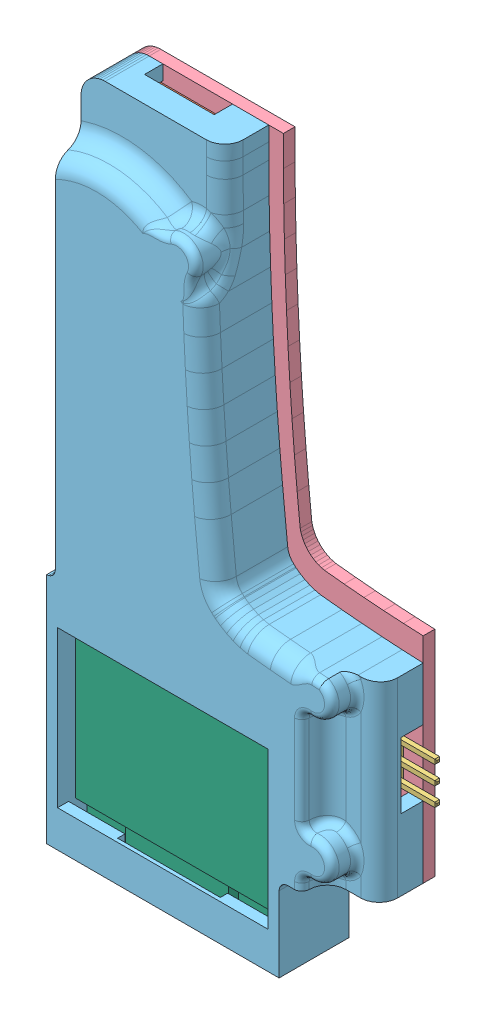
SolidWorks assembly 机身, configuration 默认. Lengths in mm.
Overall size (45.22 90.49 12.7).
35 component instances, 6 part files, 6 mates.
Components (placement in the parent):
- Controller_body-1: Controller_body [默认] at (-135.1163 108.4496 -1.41) size (44.02 78.99 5.56)
  - Controller_body.step-1: Controller_body.step [默认] at origin size (44.02 78.99 5.56)
    - R_0805_2012Metric.step-1: R_0805_2012Metric.step [默认] at (97.536 -98.298 1.63) x (-1 0 0) z (0 0 1) size (2 1.2 0.45)
      - SOLID.step-1: SOLID.step [默认] at origin size (2 1.2 0.45)
    - R_0805_2012Metric.step-2: R_0805_2012Metric.step [默认] at (85.106 -86.36 1.63) x (-1 0 0) z (0 0 1) size (2 1.2 0.45)
      - SOLID.step-1: SOLID.step [默认] at origin size (2 1.2 0.45)
    - TE_84953-6_1x06-1MP_P1.0mm_Horizontal.step-1: TE_84953-6_1x06-1MP_P1.0mm_Horizontal.step [默认] at (89.662 -56.46 1.63) x (-1 0 0) z (0 0 1) size (13.92 6.54 2.56)
      - SOLID-0.step-1: SOLID-0.step [默认] at origin size (13.92 6.54 2.56)
    - R_0805_2012Metric.step-3: R_0805_2012Metric.step [默认] at (83.82 -107.188 1.63) x (0 1 0) z (0 0 1) size (2 1.2 0.45)
      - SOLID.step-1: SOLID.step [默认] at origin size (2 1.2 0.45)
    - R_0805_2012Metric.step-4: R_0805_2012Metric.step [默认] at (102.362 -102.108 1.63) size (2 1.2 0.45)
      - SOLID.step-1: SOLID.step [默认] at origin size (2 1.2 0.45)
    - R_0805_2012Metric.step-5: R_0805_2012Metric.step [默认] at (93.218 -116.078 1.63) x (0 1 0) z (0 0 1) size (2 1.2 0.45)
      - SOLID.step-1: SOLID.step [默认] at origin size (2 1.2 0.45)
    - R_0805_2012Metric.step-6: R_0805_2012Metric.step [默认] at (85.106 -82.296 1.63) x (-1 0 0) z (0 0 1) size (2 1.2 0.45)
      - SOLID.step-1: SOLID.step [默认] at origin size (2 1.2 0.45)
    - R_0805_2012Metric.step-7: R_0805_2012Metric.step [默认] at (85.106 -84.328 1.63) x (-1 0 0) z (0 0 1) size (2 1.2 0.45)
      - SOLID.step-1: SOLID.step [默认] at origin size (2 1.2 0.45)
    - PinHeader_1x03_P2.54mm_Horizontal.step-1: PinHeader_1x03_P2.54mm_Horizontal.step [默认] at (113.735 -112.014 1.63) size (10.36 7.62 5.54)
      - SOLID-1.step-1: SOLID-1.step [默认] at origin size (10.36 7.62 5.54)
    - R_0805_2012Metric.step-8: R_0805_2012Metric.step [默认] at (85.852 -103.362 1.63) x (0 -1 0) z (0 0 1) size (2 1.2 0.45)
      - SOLID.step-1: SOLID.step [默认] at origin size (2 1.2 0.45)
    - R_0805_2012Metric.step-9: R_0805_2012Metric.step [默认] at (95.25 -116.078 1.63) x (0 1 0) z (0 0 1) size (2 1.2 0.45)
      - SOLID.step-1: SOLID.step [默认] at origin size (2 1.2 0.45)
    - R_0805_2012Metric.step-10: R_0805_2012Metric.step [默认] at (85.106 -80.264 1.63) x (-1 0 0) z (0 0 1) size (2 1.2 0.45)
      - SOLID.step-1: SOLID.step [默认] at origin size (2 1.2 0.45)
    - R_0805_2012Metric.step-11: R_0805_2012Metric.step [默认] at (91.186 -116.078 1.63) x (0 1 0) z (0 0 1) size (2 1.2 0.45)
      - SOLID.step-1: SOLID.step [默认] at origin size (2 1.2 0.45)
    - R_0805_2012Metric.step-12: R_0805_2012Metric.step [默认] at (83.82 -103.362 1.63) x (0 -1 0) z (0 0 1) size (2 1.2 0.45)
      - SOLID.step-1: SOLID.step [默认] at origin size (2 1.2 0.45)
    - R_0805_2012Metric.step-13: R_0805_2012Metric.step [默认] at (85.852 -107.188 1.63) x (0 1 0) z (0 0 1) size (2 1.2 0.45)
      - SOLID.step-1: SOLID.step [默认] at origin size (2 1.2 0.45)
    - PCB.step-1: PCB.step [默认] at origin size (40.64 78.99 1.58)
- 机身壳-1: 机身壳 [默认] at (-14.7203 -20.3284 0.17) x (1 0 0) z (0 -1 0) size (41.84 9.76 90.49)
- oled-1: oled [默认] at (-54.0243 -29.8644 5.07) x (1 0 0) z (0 -1 0) size (27.3 8.1 27.8)
Mates (geometry in assembly coordinates):
- 同心1: concentric anti-aligned: cylinder of Controller_body-1/Controller_body.step-1/PCB.step-1 through (-38.8503 45.9656 -2.2) axis (0 0 1) radius 1.6; cylinder of 机身壳-1 through (-38.8503 45.9656 4.17) axis (0 0 -1) radius 1.45
- 同心2: concentric anti-aligned: cylinder of Controller_body-1/Controller_body.step-1/PCB.step-1 through (-20.3083 3.5476 -2.2) axis (0 0 1) radius 1.6; cylinder of 机身壳-1 through (-20.3083 3.5476 4.17) axis (0 0 -1) radius 1.45
- 重合1: coincident anti-aligned: plane of Controller_body-1/Controller_body.step-1/PCB.step-1 through (-38.8551 15.1073 0.17) normal (0 0 1); plane of 机身壳-1 through (-14.7203 -20.3284 0.17) normal (0 0 -1)
- 同心3: concentric anti-aligned: cylinder of Controller_body-1/Controller_body.step-1/PCB.step-1 through (-39.1043 -3.5644 -2.2) axis (0 0 1) radius 0.381; cylinder of oled-1 through (-39.1043 -3.5644 7.07) axis (0 0 -1) radius 0.6
- 同心4: concentric anti-aligned: cylinder of Controller_body-1/Controller_body.step-1/PCB.step-1 through (-41.6443 -3.5644 -2.2) axis (0 0 1) radius 0.381; cylinder of oled-1 through (-41.6443 -3.5644 7.07) axis (0 0 -1) radius 0.6
- 重合2: coincident anti-aligned: plane of Controller_body-1/Controller_body.step-1/PCB.step-1 through (-38.8551 15.1073 0.17) normal (0 0 1); plane of oled-1 through (-54.0243 -29.8644 0.17) normal (0 0 -1)
